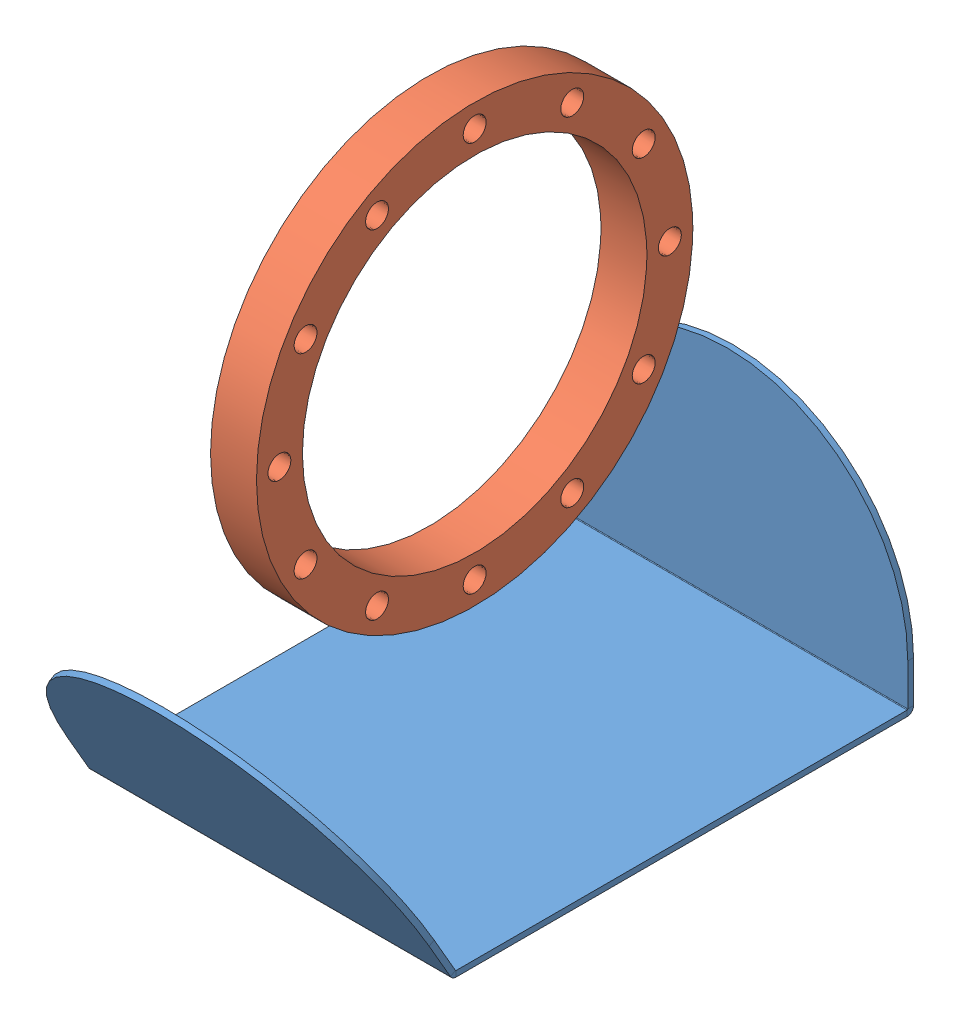
SolidWorks assembly Assem1, configuration Default. Lengths in mm.
Overall size (400 638.5 1000).
2 component instances, 2 part files, 1 mates.
Components (placement in the parent):
- Skid_Plate-1: Skid_Plate [Default] at origin size (400 253.08 1000)
- Hoop-1: Hoop [Default] at (-14.565 390.8493 39.8632) x (0 0 -1) z (1 0 0) size (482.6 482.6 50.8)
Mates (geometry in assembly coordinates):
- Coincident1: coincident: point of Hoop-1; point of assembly
